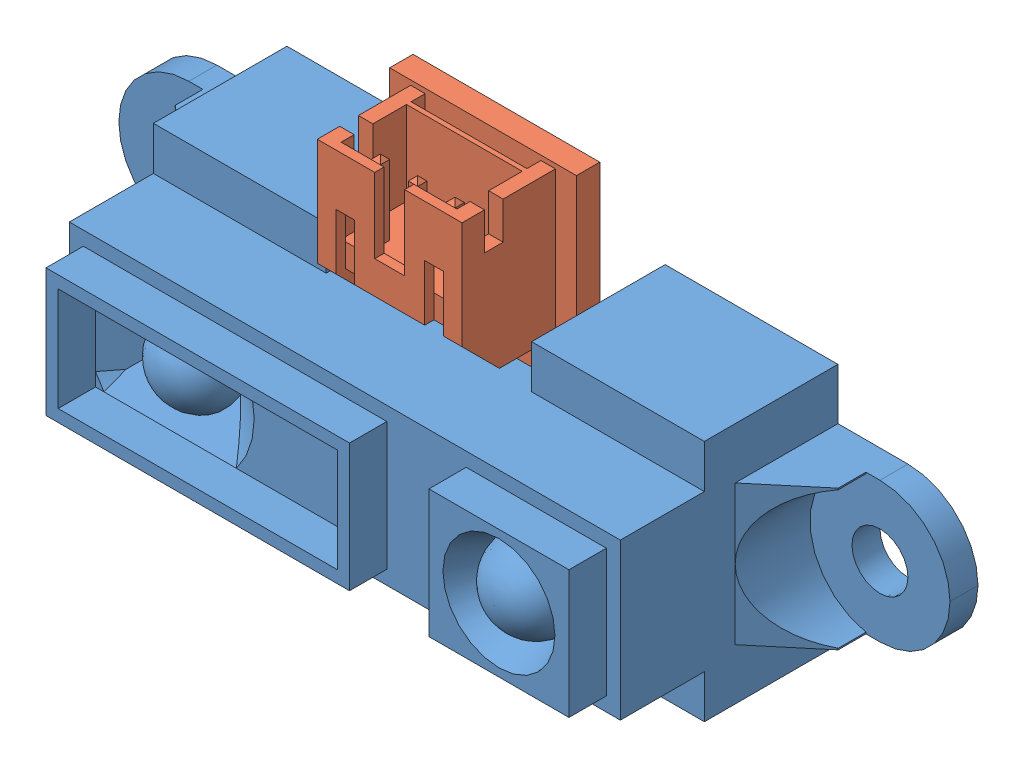
SolidWorks assembly SHARP 2Y0A21, configuration Predeterminado. Lengths in mm.
Overall size (44.5 19 13.9).
2 component instances, 2 part files, 3 mates.
Components (placement in the parent):
- SHARP 2Y0A21-1: SHARP 2Y0A21 [Predeterminado] at (-3.237 2.158 -6.95) size (44.5 13 13.9)
- SHARP 2Y0A21 elec-1: SHARP 2Y0A21 elec [Predeterminado] at (-3.237 2.158 -3.95) size (28 18 7)
Mates (geometry in assembly coordinates):
- Distancia1: distance = 3 mm: plane of SHARP 2Y0A21 elec-1 through (-3.237 -22.0657 -3.95) normal (0 0 -1); plane of SHARP 2Y0A21-1 through (-17.987 8.658 -6.95) normal (0 0 -1)
- Coincidente3: coincident: plane of SHARP 2Y0A21-1 through (-17.237 2.158 -0.95) normal (1 0 0); plane of SHARP 2Y0A21 elec-1 through (-17.237 -22.0657 -2.7) normal (-1 0 0)
- Distancia2: distance = 0.25 mm: plane of SHARP 2Y0A21 elec-1 through (-3.237 7.658 -2.7) normal (0 1 0); plane of SHARP 2Y0A21-1 through (-28.4532 7.908 -0.95) normal (0 -1 0)
